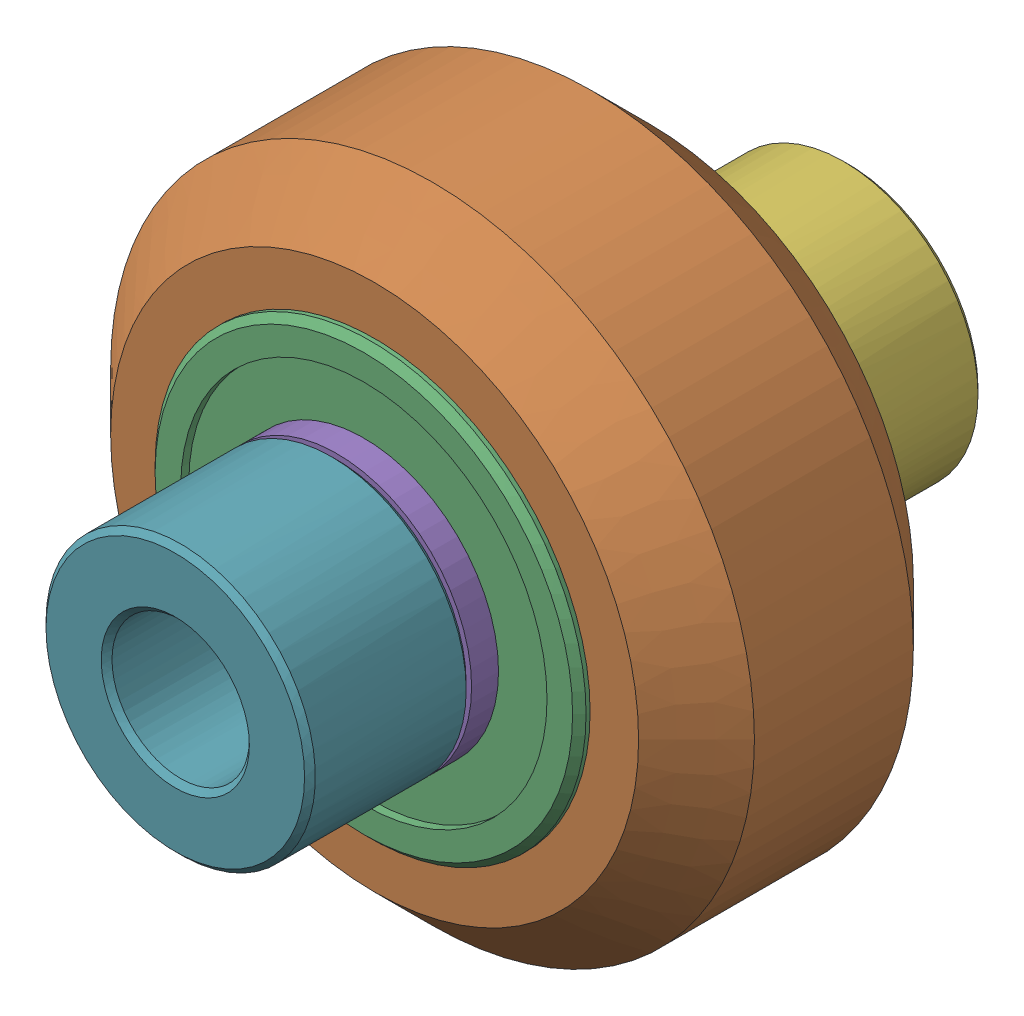
SolidWorks assembly Inboard Wheel Stack_2, configuration Default. Lengths in mm.
Overall size (23.9 23.9 25).
9 component instances, 4 part files, 0 mates.
Components (placement in the parent):
- Xtreme Solid V Wheel Kit Assembly_2-1: Xtreme Solid V Wheel Kit Assembly_2 [Default] at origin size (23.9 23.9 13)
  - Precision Shim - 10x5x1mm-1: Precision Shim - 10x5x1mm [Default] at origin size (10 10 1)
  - Xtreme Solid V Wheel Assembly_2-1: Xtreme Solid V Wheel Assembly_2 [Default] at (154.85 55 -23.5) size (23.9 23.9 11)
    - Xtreme Solid V Wheel-1: Xtreme Solid V Wheel [Default] at (-154.85 -55 30) x (0 0 1) z (-1 0 0) size (10.2 23.9 23.9)
    - Wheel+Kit+-+5x16x5mm+Sealed+Radial+Ball+Bearing.step.f3d-1: Wheel+Kit+-+5x16x5mm+Sealed+Radial+Ball+Bearing.step.f3d [Default] at (-154.85 -55 30) x (0 1 0) z (-1 0 0) size (16 5 16)
    - Wheel+Kit+-+5x16x5mm+Sealed+Radial+Ball+Bearing.step.f3d-2: Wheel+Kit+-+5x16x5mm+Sealed+Radial+Ball+Bearing.step.f3d [Default] at (-154.85 -55 30) x (0 1 0) z (1 0 0) size (16 5 16)
  - Precision Shim - 10x5x1mm-2: Precision Shim - 10x5x1mm [Default] at (0 0 12) size (10 10 1)
- Aluminum Spacer 6mm-1: Aluminum Spacer 6mm [Default] at (0 0 -6) size (10 10 6)
- Aluminum Spacer 6mm-2: Aluminum Spacer 6mm [Default] at (0 0 13) size (10 10 6)
